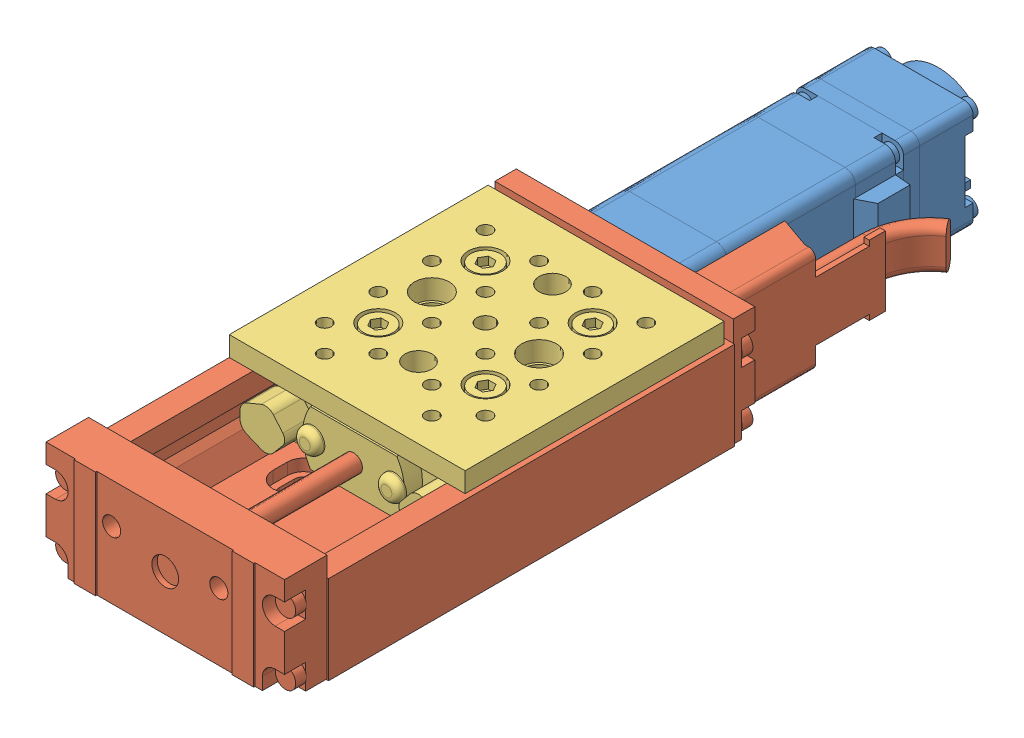
SolidWorks assembly LSM, configuration LSM025x-E03T4A. Lengths in mm.
Overall size (52.5 21 144.5).
4 component instances, 4 part files, 3 mates.
Components (placement in the parent):
- NMS08_motor^LSM-1: NMS08_motor^LSM [NMS08-E03] at origin size (23 20 66.5) (virtual)
- LSM_base^LSM-1: LSM_base^LSM [LSM025-T4A] at origin (virtual)
- LSM_carriage^LSM-1: LSM_carriage^LSM [LSM] at origin (virtual)
- LSM-V_base^LSM-1: LSM-V_base^LSM [LSM025-VT4] at origin (suppressed, hidden, virtual)
Mates (geometry in assembly coordinates):
- Coincident3: coincident aligned: plane of assembly through (0 0 0) normal (0 1 0); plane of LSM_carriage^LSM-1 through (0 0 0) normal (0 1 0)
- Coincident4: coincident aligned: plane of assembly through (0 0 0) normal (1 0 0); plane of LSM_carriage^LSM-1 through (0 0 0) normal (1 0 0)
- LimitDistance1: limit distance = 0 mm aligned: plane of LSM_carriage^LSM-1 through (0 0 0) normal (0 0 1); plane of assembly through (0 0 0) normal (0 0 1)
